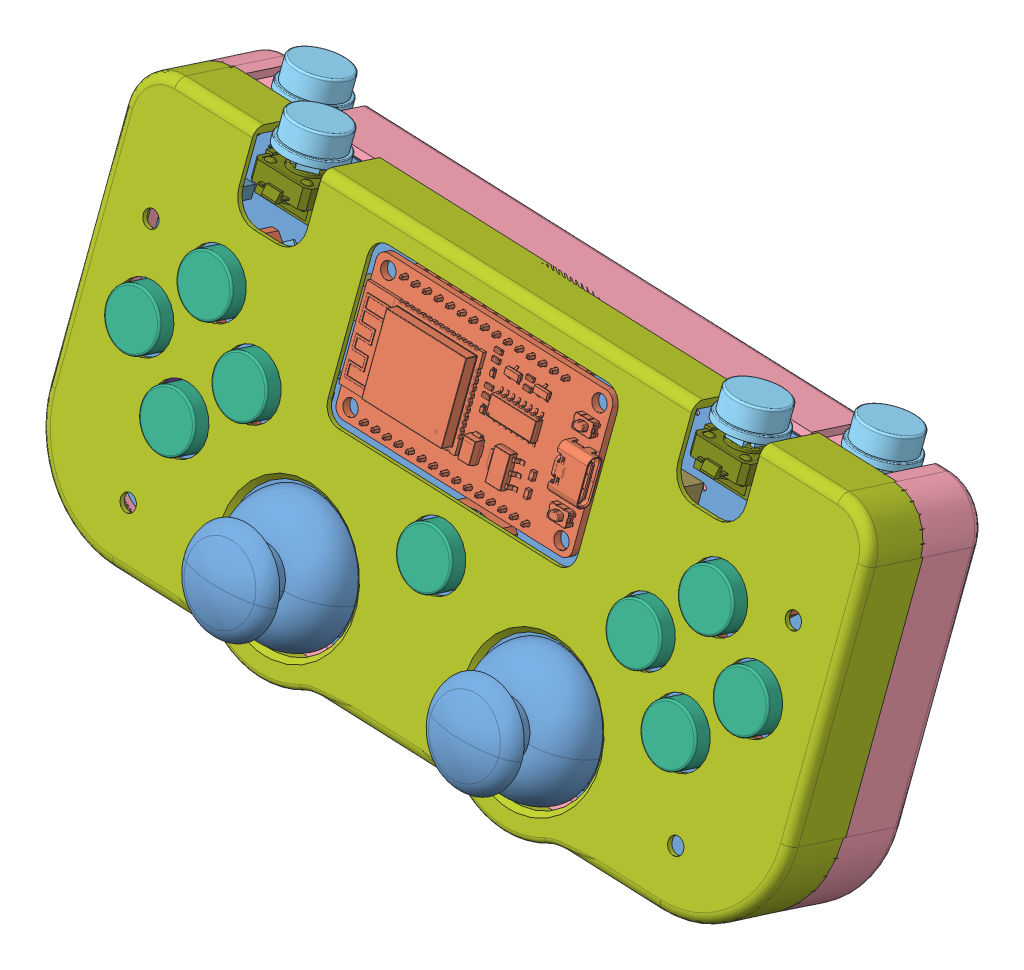
SolidWorks assembly controller, configuration Default. Lengths in mm.
Overall size (166.66 96.06 70.51).
213 component instances, 25 part files, 78 mates.
Components (placement in the parent):
- controller.step-1: controller.step [Default] at (25.4775 3.2443 108.305) x (0.999315 -0.03652 0.006033) z (0.005555 0.30909 0.951017) size (158.62 75.66 29.81)
  - Board.step-1: Board.step [Default] at origin size (158.62 74.17 0.41)
    - Open CASCADE STEP translator 7.5 1.1.1.step-1: Open CASCADE STEP translator 7.5 1.1.1.step [Default] at (0 0 -0.4115) size (158.62 74.17 0.41)
  - SW11.step-1: SW11.step [Default] at origin size (12 13.8 8.01)
    - Switch_Omron_B3F-4000_eec.step-1: Switch_Omron_B3F-4000_eec.step [Default] at (92.7295 35.2468 2.4624) x (0 1 0) z (0 0 1) size (13.8 12 8.01)
      - Omron B3F-4000 1.step-1: Omron B3F-4000 1.step [Default] at (3.1026 -5.4513 -0.4613) size (12 12 5.5)
      - Omron B3F-4000 2.step-1: Omron B3F-4000 2.step [Default] at (3.1026 -5.4513 2.5387) x (-1 0 0) z (0 0 1) size (11 11 0.5)
      - Omron B3F-4000 3.step-1: Omron B3F-4000 3.step [Default] at (3.1026 -5.4513 4.0387) x (1 0 0) z (0 0 -1) size (7.1 7.1 1.5)
      - Omron B3F-4000 4.step-1: Omron B3F-4000 4.step [Default] at (9.5526 -2.4513 -1.9613) x (1 0 0) z (0 -1 0) size (0.9 4 1)
      - Omron B3F-4000 4.step-2: Omron B3F-4000 4.step [Default] at (9.5526 -7.4513 -1.9613) x (1 0 0) z (0 -1 0) size (0.9 4 1)
      - Omron B3F-4000 4_MIR.step-1: Omron B3F-4000 4_MIR.step [Default] at (-3.3474 -2.4513 -1.9613) x (-1 0 0) z (0 1 0) size (0.9 4 1)
      - Omron B3F-4000 4_MIR.step-2: Omron B3F-4000 4_MIR.step [Default] at (-3.3474 -7.4513 -1.9613) x (-1 0 0) z (0 1 0) size (0.9 4 1)
      - Omron B3F-4000 5.step-1: Omron B3F-4000 5.step [Default] at (7.6026 -0.9513 3.0387) size (1.5 1.5 1.2)
      - Omron B3F-4000 5_MIR2.step-1: Omron B3F-4000 5_MIR2.step [Default] at (7.6026 -9.9513 3.0387) x (1 0 0) z (0 0 -1) size (1.5 1.5 1.2)
      - Omron B3F-4000 5_MIR3.step-1: Omron B3F-4000 5_MIR3.step [Default] at (-1.3974 -0.9513 3.0387) x (-1 0 0) z (0 0 -1) size (1.5 1.5 1.2)
      - Omron B3F-4000 5_MIR2_MIR.step-1: Omron B3F-4000 5_MIR2_MIR.step [Default] at (-1.3974 -9.9513 3.0387) x (-1 0 0) z (0 0 1) size (1.5 1.5 1.2)
      - Omron.step-1: Omron.step [Default] at (3.0502 -5.7952 4.0387) size (2.99 0.61 0.02)
  - SW9.step-1: SW9.step [Default] at origin size (6 6 4.5)
    - 7098939168.step-1: 7098939168.step [Default] at (64.389 64.262 0) size (6 6 4.5)
      - Extruded.step-1: Extruded.step [Default] at origin size (6 6 4.5)
  - SW10.step-1: SW10.step [Default] at origin size (6 6 4.5)
    - 7098939168.step-1: 7098939168.step [Default] at (131.953 64.262 0) size (6 6 4.5)
      - Extruded.step-1: Extruded.step [Default] at origin size (6 6 4.5)
  - C5.step-1: C5.step [Default] at origin size (3.81 2.54 11.66)
    - 7094425376.step-1: 7094425376.step [Default] at (34.6711 68.58 -7) size (0.51 0.51 7)
      - Extruded-0.step-1: Extruded-0.step [Default] at origin size (0.51 0.51 7)
    - 7094425376.step-2: 7094425376.step [Default] at (32.1311 68.5801 -7) size (0.51 0.51 7)
      - Extruded-0.step-1: Extruded-0.step [Default] at origin size (0.51 0.51 7)
    - 7098940608.step-1: 7098940608.step [Default] at (33.401 68.58 0) size (3.81 2.54 4.66)
      - Extruded-1.step-1: Extruded-1.step [Default] at origin size (3.81 2.54 4.66)
  - C6.step-1: C6.step [Default] at origin size (3.81 2.54 11.66)
    - 7094425376.step-1: 7094425376.step [Default] at (165.3541 67.31 -7) size (0.51 0.51 7)
      - Extruded-0.step-1: Extruded-0.step [Default] at origin size (0.51 0.51 7)
    - 7094425376.step-2: 7094425376.step [Default] at (162.8141 67.3101 -7) size (0.51 0.51 7)
      - Extruded-0.step-1: Extruded-0.step [Default] at origin size (0.51 0.51 7)
    - 7098940608.step-1: 7098940608.step [Default] at (164.084 67.31 0) size (3.81 2.54 4.66)
      - Extruded-1.step-1: Extruded-1.step [Default] at origin size (3.81 2.54 4.66)
  - S4.step-1: S4.step [Default] at origin size (13.1 13.3 18.3)
    - 6508629744.step-1: 6508629744.step [Default] at (160.742 77.978 -0.4115) x (0 -1 0) z (1 0 0) size (13.3 18.3 13.1)
  - S3.step-1: S3.step [Default] at origin size (13.1 13.3 18.3)
    - 6508631584.step-1: 6508631584.step [Default] at (146.344 77.978 0) x (0 -1 0) z (-1 0 0) size (13.3 18.3 13.1)
  - S2.step-1: S2.step [Default] at origin size (13.1 13.3 18.3)
    - 6508631584.step-1: 6508631584.step [Default] at (49.744 77.978 0) x (0 -1 0) z (-1 0 0) size (13.3 18.3 13.1)
  - S1.step-1: S1.step [Default] at origin size (13.1 13.3 18.3)
    - 6508629744.step-1: 6508629744.step [Default] at (35.346 77.978 -0.4115) x (0 -1 0) z (1 0 0) size (13.3 18.3 13.1)
  - C4.step-1: C4.step [Default] at origin size (4.49 4.49 11.66)
    - 7094425376.step-1: 7094425376.step [Default] at (30.4371 33.138 -7) size (0.51 0.51 7)
      - Extruded-0.step-1: Extruded-0.step [Default] at origin size (0.51 0.51 7)
    - 7094425376.step-2: 7094425376.step [Default] at (28.6411 34.9341 -7) size (0.51 0.51 7)
      - Extruded-0.step-1: Extruded-0.step [Default] at origin size (0.51 0.51 7)
    - 7094424896.step-1: 7094424896.step [Default] at (29.5392 34.036 0) size (4.49 4.49 4.66)
      - Extruded-2.step-1: Extruded-2.step [Default] at origin size (4.49 4.49 4.66)
  - C3.step-1: C3.step [Default] at origin size (4.49 4.49 11.66)
    - 7094425376.step-1: 7094425376.step [Default] at (166.7082 33.9179 -7) size (0.51 0.51 7)
      - Extruded-0.step-1: Extruded-0.step [Default] at origin size (0.51 0.51 7)
    - 7094425376.step-2: 7094425376.step [Default] at (164.9122 32.1219 -7) size (0.51 0.51 7)
      - Extruded-0.step-1: Extruded-0.step [Default] at origin size (0.51 0.51 7)
    - 7098938768.step-1: 7098938768.step [Default] at (165.8102 33.02 0) size (4.49 4.49 4.66)
      - Extruded-3.step-1: Extruded-3.step [Default] at origin size (4.49 4.49 4.66)
  - C2.step-1: C2.step [Default] at origin size (4.49 4.49 11.66)
    - 7094425376.step-1: 7094425376.step [Default] at (55.4293 60.9781 -7) size (0.51 0.51 7)
      - Extruded-0.step-1: Extruded-0.step [Default] at origin size (0.51 0.51 7)
    - 7094425376.step-2: 7094425376.step [Default] at (57.2253 59.182 -7) size (0.51 0.51 7)
      - Extruded-0.step-1: Extruded-0.step [Default] at origin size (0.51 0.51 7)
    - 7094424896.step-1: 7094424896.step [Default] at (56.3272 60.08 0) size (4.49 4.49 4.66)
      - Extruded-2.step-1: Extruded-2.step [Default] at origin size (4.49 4.49 4.66)
  - C1.step-1: C1.step [Default] at origin size (4.49 4.49 11.66)
    - 7094425376.step-1: 7094425376.step [Default] at (139.5122 58.4111 -7) size (0.51 0.51 7)
      - Extruded-0.step-1: Extruded-0.step [Default] at origin size (0.51 0.51 7)
    - 7094425376.step-2: 7094425376.step [Default] at (141.3083 60.2071 -7) size (0.51 0.51 7)
      - Extruded-0.step-1: Extruded-0.step [Default] at origin size (0.51 0.51 7)
    - 7098938768.step-1: 7098938768.step [Default] at (140.4102 59.309 0) size (4.49 4.49 4.66)
      - Extruded-3.step-1: Extruded-3.step [Default] at origin size (4.49 4.49 4.66)
  - SW1.step-1: SW1.step [Default] at origin size (18.24 18.24 8.01)
    - Switch_Omron_B3F-4000_eec.step-1: Switch_Omron_B3F-4000_eec.step [Default] at (48.6404 48.2596 2.4624) x (0.707107 0.707107 0) z (0 0 1) size (13.8 12 8.01)
      - Omron B3F-4000 1.step-1: Omron B3F-4000 1.step [Default] at (3.1026 -5.4513 -0.4613) size (12 12 5.5)
      - Omron B3F-4000 2.step-1: Omron B3F-4000 2.step [Default] at (3.1026 -5.4513 2.5387) x (-1 0 0) z (0 0 1) size (11 11 0.5)
      - Omron B3F-4000 3.step-1: Omron B3F-4000 3.step [Default] at (3.1026 -5.4513 4.0387) x (1 0 0) z (0 0 -1) size (7.1 7.1 1.5)
      - Omron B3F-4000 4.step-1: Omron B3F-4000 4.step [Default] at (9.5526 -2.4513 -1.9613) x (1 0 0) z (0 -1 0) size (0.9 4 1)
      - Omron B3F-4000 4.step-2: Omron B3F-4000 4.step [Default] at (9.5526 -7.4513 -1.9613) x (1 0 0) z (0 -1 0) size (0.9 4 1)
      - Omron B3F-4000 4_MIR.step-1: Omron B3F-4000 4_MIR.step [Default] at (-3.3474 -2.4513 -1.9613) x (-1 0 0) z (0 1 0) size (0.9 4 1)
      - Omron B3F-4000 4_MIR.step-2: Omron B3F-4000 4_MIR.step [Default] at (-3.3474 -7.4513 -1.9613) x (-1 0 0) z (0 1 0) size (0.9 4 1)
      - Omron B3F-4000 5.step-1: Omron B3F-4000 5.step [Default] at (7.6026 -0.9513 3.0387) size (1.5 1.5 1.2)
      - Omron B3F-4000 5_MIR2.step-1: Omron B3F-4000 5_MIR2.step [Default] at (7.6026 -9.9513 3.0387) x (1 0 0) z (0 0 -1) size (1.5 1.5 1.2)
      - Omron B3F-4000 5_MIR3.step-1: Omron B3F-4000 5_MIR3.step [Default] at (-1.3974 -0.9513 3.0387) x (-1 0 0) z (0 0 -1) size (1.5 1.5 1.2)
      - Omron B3F-4000 5_MIR2_MIR.step-1: Omron B3F-4000 5_MIR2_MIR.step [Default] at (-1.3974 -9.9513 3.0387) x (-1 0 0) z (0 0 1) size (1.5 1.5 1.2)
      - Omron.step-1: Omron.step [Default] at (3.0502 -5.7952 4.0387) size (2.99 0.61 0.02)
  - SW2.step-1: SW2.step [Default] at origin size (18.24 18.24 8.01)
    - Switch_Omron_B3F-4000_eec.step-1: Switch_Omron_B3F-4000_eec.step [Default] at (36.8294 60.0706 2.4624) x (0.707107 0.707107 0) z (0 0 1) size (13.8 12 8.01)
      - Omron B3F-4000 1.step-1: Omron B3F-4000 1.step [Default] at (3.1026 -5.4513 -0.4613) size (12 12 5.5)
      - Omron B3F-4000 2.step-1: Omron B3F-4000 2.step [Default] at (3.1026 -5.4513 2.5387) x (-1 0 0) z (0 0 1) size (11 11 0.5)
      - Omron B3F-4000 3.step-1: Omron B3F-4000 3.step [Default] at (3.1026 -5.4513 4.0387) x (1 0 0) z (0 0 -1) size (7.1 7.1 1.5)
      - Omron B3F-4000 4.step-1: Omron B3F-4000 4.step [Default] at (9.5526 -2.4513 -1.9613) x (1 0 0) z (0 -1 0) size (0.9 4 1)
      - Omron B3F-4000 4.step-2: Omron B3F-4000 4.step [Default] at (9.5526 -7.4513 -1.9613) x (1 0 0) z (0 -1 0) size (0.9 4 1)
      - Omron B3F-4000 4_MIR.step-1: Omron B3F-4000 4_MIR.step [Default] at (-3.3474 -2.4513 -1.9613) x (-1 0 0) z (0 1 0) size (0.9 4 1)
      - Omron B3F-4000 4_MIR.step-2: Omron B3F-4000 4_MIR.step [Default] at (-3.3474 -7.4513 -1.9613) x (-1 0 0) z (0 1 0) size (0.9 4 1)
      - Omron B3F-4000 5.step-1: Omron B3F-4000 5.step [Default] at (7.6026 -0.9513 3.0387) size (1.5 1.5 1.2)
      - Omron B3F-4000 5_MIR2.step-1: Omron B3F-4000 5_MIR2.step [Default] at (7.6026 -9.9513 3.0387) x (1 0 0) z (0 0 -1) size (1.5 1.5 1.2)
      - Omron B3F-4000 5_MIR3.step-1: Omron B3F-4000 5_MIR3.step [Default] at (-1.3974 -0.9513 3.0387) x (-1 0 0) z (0 0 -1) size (1.5 1.5 1.2)
      - Omron B3F-4000 5_MIR2_MIR.step-1: Omron B3F-4000 5_MIR2_MIR.step [Default] at (-1.3974 -9.9513 3.0387) x (-1 0 0) z (0 0 1) size (1.5 1.5 1.2)
      - Omron.step-1: Omron.step [Default] at (3.0502 -5.7952 4.0387) size (2.99 0.61 0.02)
  - SW3.step-1: SW3.step [Default] at origin size (18.24 18.24 8.01)
    - Switch_Omron_B3F-4000_eec.step-1: Switch_Omron_B3F-4000_eec.step [Default] at (25.0184 48.2596 2.4624) x (0.707107 0.707107 0) z (0 0 1) size (13.8 12 8.01)
      - Omron B3F-4000 1.step-1: Omron B3F-4000 1.step [Default] at (3.1026 -5.4513 -0.4613) size (12 12 5.5)
      - Omron B3F-4000 2.step-1: Omron B3F-4000 2.step [Default] at (3.1026 -5.4513 2.5387) x (-1 0 0) z (0 0 1) size (11 11 0.5)
      - Omron B3F-4000 3.step-1: Omron B3F-4000 3.step [Default] at (3.1026 -5.4513 4.0387) x (1 0 0) z (0 0 -1) size (7.1 7.1 1.5)
      - Omron B3F-4000 4.step-1: Omron B3F-4000 4.step [Default] at (9.5526 -2.4513 -1.9613) x (1 0 0) z (0 -1 0) size (0.9 4 1)
      - Omron B3F-4000 4.step-2: Omron B3F-4000 4.step [Default] at (9.5526 -7.4513 -1.9613) x (1 0 0) z (0 -1 0) size (0.9 4 1)
      - Omron B3F-4000 4_MIR.step-1: Omron B3F-4000 4_MIR.step [Default] at (-3.3474 -2.4513 -1.9613) x (-1 0 0) z (0 1 0) size (0.9 4 1)
      - Omron B3F-4000 4_MIR.step-2: Omron B3F-4000 4_MIR.step [Default] at (-3.3474 -7.4513 -1.9613) x (-1 0 0) z (0 1 0) size (0.9 4 1)
      - Omron B3F-4000 5.step-1: Omron B3F-4000 5.step [Default] at (7.6026 -0.9513 3.0387) size (1.5 1.5 1.2)
      - Omron B3F-4000 5_MIR2.step-1: Omron B3F-4000 5_MIR2.step [Default] at (7.6026 -9.9513 3.0387) x (1 0 0) z (0 0 -1) size (1.5 1.5 1.2)
      - Omron B3F-4000 5_MIR3.step-1: Omron B3F-4000 5_MIR3.step [Default] at (-1.3974 -0.9513 3.0387) x (-1 0 0) z (0 0 -1) size (1.5 1.5 1.2)
      - Omron B3F-4000 5_MIR2_MIR.step-1: Omron B3F-4000 5_MIR2_MIR.step [Default] at (-1.3974 -9.9513 3.0387) x (-1 0 0) z (0 0 1) size (1.5 1.5 1.2)
      - Omron.step-1: Omron.step [Default] at (3.0502 -5.7952 4.0387) size (2.99 0.61 0.02)
  - SW4.step-1: SW4.step [Default] at origin size (18.24 18.24 8.01)
    - Switch_Omron_B3F-4000_eec.step-1: Switch_Omron_B3F-4000_eec.step [Default] at (36.8294 36.4486 2.4624) x (0.707107 0.707107 0) z (0 0 1) size (13.8 12 8.01)
      - Omron B3F-4000 1.step-1: Omron B3F-4000 1.step [Default] at (3.1026 -5.4513 -0.4613) size (12 12 5.5)
      - Omron B3F-4000 2.step-1: Omron B3F-4000 2.step [Default] at (3.1026 -5.4513 2.5387) x (-1 0 0) z (0 0 1) size (11 11 0.5)
      - Omron B3F-4000 3.step-1: Omron B3F-4000 3.step [Default] at (3.1026 -5.4513 4.0387) x (1 0 0) z (0 0 -1) size (7.1 7.1 1.5)
      - Omron B3F-4000 4.step-1: Omron B3F-4000 4.step [Default] at (9.5526 -2.4513 -1.9613) x (1 0 0) z (0 -1 0) size (0.9 4 1)
      - Omron B3F-4000 4.step-2: Omron B3F-4000 4.step [Default] at (9.5526 -7.4513 -1.9613) x (1 0 0) z (0 -1 0) size (0.9 4 1)
      - Omron B3F-4000 4_MIR.step-1: Omron B3F-4000 4_MIR.step [Default] at (-3.3474 -2.4513 -1.9613) x (-1 0 0) z (0 1 0) size (0.9 4 1)
      - Omron B3F-4000 4_MIR.step-2: Omron B3F-4000 4_MIR.step [Default] at (-3.3474 -7.4513 -1.9613) x (-1 0 0) z (0 1 0) size (0.9 4 1)
      - Omron B3F-4000 5.step-1: Omron B3F-4000 5.step [Default] at (7.6026 -0.9513 3.0387) size (1.5 1.5 1.2)
      - Omron B3F-4000 5_MIR2.step-1: Omron B3F-4000 5_MIR2.step [Default] at (7.6026 -9.9513 3.0387) x (1 0 0) z (0 0 -1) size (1.5 1.5 1.2)
      - Omron B3F-4000 5_MIR3.step-1: Omron B3F-4000 5_MIR3.step [Default] at (-1.3974 -0.9513 3.0387) x (-1 0 0) z (0 0 -1) size (1.5 1.5 1.2)
      - Omron B3F-4000 5_MIR2_MIR.step-1: Omron B3F-4000 5_MIR2_MIR.step [Default] at (-1.3974 -9.9513 3.0387) x (-1 0 0) z (0 0 1) size (1.5 1.5 1.2)
      - Omron.step-1: Omron.step [Default] at (3.0502 -5.7952 4.0387) size (2.99 0.61 0.02)
  - SW8.step-1: SW8.step [Default] at origin size (18.24 18.24 8.01)
    - Switch_Omron_B3F-4000_eec.step-1: Switch_Omron_B3F-4000_eec.step [Default] at (147.1924 36.4486 2.4624) x (0.707107 0.707107 0) z (0 0 1) size (13.8 12 8.01)
      - Omron B3F-4000 1.step-1: Omron B3F-4000 1.step [Default] at (3.1026 -5.4513 -0.4613) size (12 12 5.5)
      - Omron B3F-4000 2.step-1: Omron B3F-4000 2.step [Default] at (3.1026 -5.4513 2.5387) x (-1 0 0) z (0 0 1) size (11 11 0.5)
      - Omron B3F-4000 3.step-1: Omron B3F-4000 3.step [Default] at (3.1026 -5.4513 4.0387) x (1 0 0) z (0 0 -1) size (7.1 7.1 1.5)
      - Omron B3F-4000 4.step-1: Omron B3F-4000 4.step [Default] at (9.5526 -2.4513 -1.9613) x (1 0 0) z (0 -1 0) size (0.9 4 1)
      - Omron B3F-4000 4.step-2: Omron B3F-4000 4.step [Default] at (9.5526 -7.4513 -1.9613) x (1 0 0) z (0 -1 0) size (0.9 4 1)
      - Omron B3F-4000 4_MIR.step-1: Omron B3F-4000 4_MIR.step [Default] at (-3.3474 -2.4513 -1.9613) x (-1 0 0) z (0 1 0) size (0.9 4 1)
      - Omron B3F-4000 4_MIR.step-2: Omron B3F-4000 4_MIR.step [Default] at (-3.3474 -7.4513 -1.9613) x (-1 0 0) z (0 1 0) size (0.9 4 1)
      - Omron B3F-4000 5.step-1: Omron B3F-4000 5.step [Default] at (7.6026 -0.9513 3.0387) size (1.5 1.5 1.2)
      - Omron B3F-4000 5_MIR2.step-1: Omron B3F-4000 5_MIR2.step [Default] at (7.6026 -9.9513 3.0387) x (1 0 0) z (0 0 -1) size (1.5 1.5 1.2)
      - Omron B3F-4000 5_MIR3.step-1: Omron B3F-4000 5_MIR3.step [Default] at (-1.3974 -0.9513 3.0387) x (-1 0 0) z (0 0 -1) size (1.5 1.5 1.2)
      - Omron B3F-4000 5_MIR2_MIR.step-1: Omron B3F-4000 5_MIR2_MIR.step [Default] at (-1.3974 -9.9513 3.0387) x (-1 0 0) z (0 0 1) size (1.5 1.5 1.2)
      - Omron.step-1: Omron.step [Default] at (3.0502 -5.7952 4.0387) size (2.99 0.61 0.02)
  - SW7.step-1: SW7.step [Default] at origin size (18.24 18.24 8.01)
    - Switch_Omron_B3F-4000_eec.step-1: Switch_Omron_B3F-4000_eec.step [Default] at (135.3813 48.2596 2.4624) x (0.707107 0.707107 0) z (0 0 1) size (13.8 12 8.01)
      - Omron B3F-4000 1.step-1: Omron B3F-4000 1.step [Default] at (3.1026 -5.4513 -0.4613) size (12 12 5.5)
      - Omron B3F-4000 2.step-1: Omron B3F-4000 2.step [Default] at (3.1026 -5.4513 2.5387) x (-1 0 0) z (0 0 1) size (11 11 0.5)
      - Omron B3F-4000 3.step-1: Omron B3F-4000 3.step [Default] at (3.1026 -5.4513 4.0387) x (1 0 0) z (0 0 -1) size (7.1 7.1 1.5)
      - Omron B3F-4000 4.step-1: Omron B3F-4000 4.step [Default] at (9.5526 -2.4513 -1.9613) x (1 0 0) z (0 -1 0) size (0.9 4 1)
      - Omron B3F-4000 4.step-2: Omron B3F-4000 4.step [Default] at (9.5526 -7.4513 -1.9613) x (1 0 0) z (0 -1 0) size (0.9 4 1)
      - Omron B3F-4000 4_MIR.step-1: Omron B3F-4000 4_MIR.step [Default] at (-3.3474 -2.4513 -1.9613) x (-1 0 0) z (0 1 0) size (0.9 4 1)
      - Omron B3F-4000 4_MIR.step-2: Omron B3F-4000 4_MIR.step [Default] at (-3.3474 -7.4513 -1.9613) x (-1 0 0) z (0 1 0) size (0.9 4 1)
      - Omron B3F-4000 5.step-1: Omron B3F-4000 5.step [Default] at (7.6026 -0.9513 3.0387) size (1.5 1.5 1.2)
      - Omron B3F-4000 5_MIR2.step-1: Omron B3F-4000 5_MIR2.step [Default] at (7.6026 -9.9513 3.0387) x (1 0 0) z (0 0 -1) size (1.5 1.5 1.2)
      - Omron B3F-4000 5_MIR3.step-1: Omron B3F-4000 5_MIR3.step [Default] at (-1.3974 -0.9513 3.0387) x (-1 0 0) z (0 0 -1) size (1.5 1.5 1.2)
      - Omron B3F-4000 5_MIR2_MIR.step-1: Omron B3F-4000 5_MIR2_MIR.step [Default] at (-1.3974 -9.9513 3.0387) x (-1 0 0) z (0 0 1) size (1.5 1.5 1.2)
      - Omron.step-1: Omron.step [Default] at (3.0502 -5.7952 4.0387) size (2.99 0.61 0.02)
  - SW6.step-1: SW6.step [Default] at origin size (18.24 18.24 8.01)
    - Switch_Omron_B3F-4000_eec.step-1: Switch_Omron_B3F-4000_eec.step [Default] at (147.1924 60.0706 2.4624) x (0.707107 0.707107 0) z (0 0 1) size (13.8 12 8.01)
      - Omron B3F-4000 1.step-1: Omron B3F-4000 1.step [Default] at (3.1026 -5.4513 -0.4613) size (12 12 5.5)
      - Omron B3F-4000 2.step-1: Omron B3F-4000 2.step [Default] at (3.1026 -5.4513 2.5387) x (-1 0 0) z (0 0 1) size (11 11 0.5)
      - Omron B3F-4000 3.step-1: Omron B3F-4000 3.step [Default] at (3.1026 -5.4513 4.0387) x (1 0 0) z (0 0 -1) size (7.1 7.1 1.5)
      - Omron B3F-4000 4.step-1: Omron B3F-4000 4.step [Default] at (9.5526 -2.4513 -1.9613) x (1 0 0) z (0 -1 0) size (0.9 4 1)
      - Omron B3F-4000 4.step-2: Omron B3F-4000 4.step [Default] at (9.5526 -7.4513 -1.9613) x (1 0 0) z (0 -1 0) size (0.9 4 1)
      - Omron B3F-4000 4_MIR.step-1: Omron B3F-4000 4_MIR.step [Default] at (-3.3474 -2.4513 -1.9613) x (-1 0 0) z (0 1 0) size (0.9 4 1)
      - Omron B3F-4000 4_MIR.step-2: Omron B3F-4000 4_MIR.step [Default] at (-3.3474 -7.4513 -1.9613) x (-1 0 0) z (0 1 0) size (0.9 4 1)
      - Omron B3F-4000 5.step-1: Omron B3F-4000 5.step [Default] at (7.6026 -0.9513 3.0387) size (1.5 1.5 1.2)
      - Omron B3F-4000 5_MIR2.step-1: Omron B3F-4000 5_MIR2.step [Default] at (7.6026 -9.9513 3.0387) x (1 0 0) z (0 0 -1) size (1.5 1.5 1.2)
      - Omron B3F-4000 5_MIR3.step-1: Omron B3F-4000 5_MIR3.step [Default] at (-1.3974 -0.9513 3.0387) x (-1 0 0) z (0 0 -1) size (1.5 1.5 1.2)
      - Omron B3F-4000 5_MIR2_MIR.step-1: Omron B3F-4000 5_MIR2_MIR.step [Default] at (-1.3974 -9.9513 3.0387) x (-1 0 0) z (0 0 1) size (1.5 1.5 1.2)
      - Omron.step-1: Omron.step [Default] at (3.0502 -5.7952 4.0387) size (2.99 0.61 0.02)
  - SW5.step-1: SW5.step [Default] at origin size (18.24 18.24 8.01)
    - Switch_Omron_B3F-4000_eec.step-1: Switch_Omron_B3F-4000_eec.step [Default] at (159.0034 48.2596 2.4624) x (0.707107 0.707107 0) z (0 0 1) size (13.8 12 8.01)
      - Omron B3F-4000 1.step-1: Omron B3F-4000 1.step [Default] at (3.1026 -5.4513 -0.4613) size (12 12 5.5)
      - Omron B3F-4000 2.step-1: Omron B3F-4000 2.step [Default] at (3.1026 -5.4513 2.5387) x (-1 0 0) z (0 0 1) size (11 11 0.5)
      - Omron B3F-4000 3.step-1: Omron B3F-4000 3.step [Default] at (3.1026 -5.4513 4.0387) x (1 0 0) z (0 0 -1) size (7.1 7.1 1.5)
      - Omron B3F-4000 4.step-1: Omron B3F-4000 4.step [Default] at (9.5526 -2.4513 -1.9613) x (1 0 0) z (0 -1 0) size (0.9 4 1)
      - Omron B3F-4000 4.step-2: Omron B3F-4000 4.step [Default] at (9.5526 -7.4513 -1.9613) x (1 0 0) z (0 -1 0) size (0.9 4 1)
      - Omron B3F-4000 4_MIR.step-1: Omron B3F-4000 4_MIR.step [Default] at (-3.3474 -2.4513 -1.9613) x (-1 0 0) z (0 1 0) size (0.9 4 1)
      - Omron B3F-4000 4_MIR.step-2: Omron B3F-4000 4_MIR.step [Default] at (-3.3474 -7.4513 -1.9613) x (-1 0 0) z (0 1 0) size (0.9 4 1)
      - Omron B3F-4000 5.step-1: Omron B3F-4000 5.step [Default] at (7.6026 -0.9513 3.0387) size (1.5 1.5 1.2)
      - Omron B3F-4000 5_MIR2.step-1: Omron B3F-4000 5_MIR2.step [Default] at (7.6026 -9.9513 3.0387) x (1 0 0) z (0 0 -1) size (1.5 1.5 1.2)
      - Omron B3F-4000 5_MIR3.step-1: Omron B3F-4000 5_MIR3.step [Default] at (-1.3974 -0.9513 3.0387) x (-1 0 0) z (0 0 -1) size (1.5 1.5 1.2)
      - Omron B3F-4000 5_MIR2_MIR.step-1: Omron B3F-4000 5_MIR2_MIR.step [Default] at (-1.3974 -9.9513 3.0387) x (-1 0 0) z (0 0 1) size (1.5 1.5 1.2)
      - Omron.step-1: Omron.step [Default] at (3.0502 -5.7952 4.0387) size (2.99 0.61 0.02)
- COM-09032-1: COM-09032 [Default] at (97.4277 22.5889 101.5976) x (0.999315 -0.03652 0.006033) z (-0.036596 -0.950331 0.309081) size (26.67 34.67 27.62)
- COM-09032-2: COM-09032 [Default] at (151.2136 20.6099 101.9266) x (0.999315 -0.03652 0.006033) z (-0.036596 -0.950331 0.309081) size (26.67 34.67 27.62)
- esp32_30pin-1: esp32_30pin [По умолчанию] at (148.2005 52.2986 104.8892) x (0.036596 0.950331 -0.309081) z (0.005555 0.30909 0.951017) size (29 52.96 13.53)
- powerboost 1000c.f3d v3-1: powerboost 1000c.f3d v3 [Default] at (151.8493 9.8112 109.6265) x (0.036596 0.950331 -0.309081) z (-0.005555 -0.30909 -0.951017) size (36.64 22.86 4.38)
- Part1-1: Part1 [Default] at (45.204 24.8437 87.0675) x (0.999315 -0.03652 0.006033) z (-0.036596 -0.950331 0.309081) size (163.63 14.65 81.83)
- 12mm Push Button Cap-1: 12mm Push Button Cap [Default] at (179.9154 32.315 103.4225) x (0.640311 -0.731594 0.234035) z (-0.768096 -0.607647 0.201977) size (13 8.2 13)
- 12mm Push Button Cap-2: 12mm Push Button Cap [Default] at (180.7799 54.7638 96.1214) x (0.640311 -0.731594 0.234035) z (-0.768096 -0.607647 0.201977) size (13 8.2 13)
- 12mm Push Button Cap-3: 12mm Push Button Cap [Default] at (168.5447 43.9708 99.7007) x (0.640311 -0.731594 0.234035) z (-0.768096 -0.607647 0.201977) size (13 8.2 13)
- 12mm Push Button Cap-4: 12mm Push Button Cap [Default] at (192.1505 43.1081 99.8432) x (0.191146 0.933167 -0.304405) z (0.981546 -0.183474 0.053898) size (13 8.2 13)
- 12mm Push Button Cap-5: 12mm Push Button Cap [Default] at (125.0234 37.7106 101.9895) x (0.640311 -0.731594 0.234035) z (-0.768096 -0.607647 0.201977) size (13 8.2 13)
- 12mm Push Button Cap TALL-1: 12mm Push Button Cap TALL [Default] at (192.1505 43.1081 99.8432) x (-0.613772 -0.749763 0.247265) z (-0.789464 0.585081 -0.185546) size (13 12.9 13)
- top_plate-1: top_plate [Default] at (203.8676 27.2141 113.1422) x (-0.999315 0.03652 -0.006033) z (-0.036596 -0.950331 0.309081) size (163.63 13.51 81.83)
- 12mm Push Button Cap-6: 12mm Push Button Cap [Default] at (58.2574 48.0013 99.0349) x (0.7195 -0.661708 0.210859) z (-0.69447 -0.683086 0.226066) size (13 8.2 13)
- 12mm Push Button Cap-7: 12mm Push Button Cap [Default] at (70.4925 58.7943 95.4556) x (0.640311 -0.731594 0.234035) z (-0.768096 -0.607647 0.201977) size (13 8.2 13)
- 12mm Push Button Cap-8: 12mm Push Button Cap [Default] at (69.628 36.3456 102.7567) x (0.640311 -0.731594 0.234035) z (-0.768096 -0.607647 0.201977) size (13 8.2 13)
- 12mm Push Button Cap-9: 12mm Push Button Cap [Default] at (81.8632 47.1386 99.1774) x (0.640311 -0.731594 0.234035) z (-0.768096 -0.607647 0.201977) size (13 8.2 13)
- 12mm Push Button Cap TALL-6: 12mm Push Button Cap TALL [Default] at (180.7799 54.7638 96.1214) x (-0.999145 0.040688 -0.007388) z (0.040979 0.950162 -0.309051) size (13 12.9 13)
- 12mm Push Button Cap TALL-7: 12mm Push Button Cap TALL [Default] at (125.0234 37.7106 101.9895) x (-0.613772 -0.749763 0.247265) z (-0.789464 0.585081 -0.185546) size (13 12.9 13)
- 12mm Push Button Cap TALL-8: 12mm Push Button Cap TALL [Default] at (58.2574 48.0013 99.0349) x (-0.502403 -0.821427 0.269906) z (-0.864616 0.479293 -0.150725) size (13 12.9 13)
- 12mm Push Button Cap TALL-9: 12mm Push Button Cap TALL [Default] at (69.628 36.3456 102.7567) x (-0.776873 -0.597476 0.198723) z (-0.629633 0.739923 -0.236805) size (13 12.9 13)
- 12mm Push Button Cap TALL-10: 12mm Push Button Cap TALL [Default] at (168.5447 43.9708 99.7007) x (-0.613772 -0.749763 0.247265) z (-0.789464 0.585081 -0.185546) size (13 12.9 13)
- 12mm Push Button Cap TALL-11: 12mm Push Button Cap TALL [Default] at (179.9154 32.315 103.4225) x (-0.613772 -0.749763 0.247265) z (-0.789464 0.585081 -0.185546) size (13 12.9 13)
- 12mm Push Button Cap TALL-12: 12mm Push Button Cap TALL [Default] at (70.4925 58.7943 95.4556) x (-0.78112 -0.592451 0.197115) z (-0.624357 0.743953 -0.238145) size (13 12.9 13)
- 12mm Push Button Cap TALL-13: 12mm Push Button Cap TALL [Default] at (81.8632 47.1386 99.1774) x (-0.613772 -0.749763 0.247265) z (-0.789464 0.585081 -0.185546) size (13 12.9 13)
- 12mm Push Button Cap-10: 12mm Push Button Cap [Default] at (174.8391 80.1008 90.3398) x (0.005555 0.30909 0.951017) z (-0.999315 0.03652 -0.006033) size (13 8.2 13)
- 12mm Push Button Cap-11: 12mm Push Button Cap [Default] at (189.1416 74.8115 75.7701) x (0.285665 -0.30633 -0.908051) z (0.95763 0.055062 0.282687) size (13 8.2 13)
- 12mm Push Button Cap-12: 12mm Push Button Cap [Default] at (63.8315 79.391 75.0136) x (0.654 0.211082 0.72645) z (-0.755609 0.228724 0.613792) size (13 8.2 13)
- 12mm Push Button Cap-13: 12mm Push Button Cap [Default] at (78.3053 83.6287 89.757) x (0.680165 0.202908 0.704417) z (-0.732145 0.236005 0.638957) size (13 8.2 13)
Mates (geometry in assembly coordinates):
- Coincident2: coincident anti-aligned: plane of controller.step-1/Board.step-1/Open CASCADE STEP translator 7.5 1.1.1.step-1 through (125.235 44.2553 94.3933) normal (0.005555 0.30909 0.951017); plane of COM-09032-1 through (97.4277 22.5889 101.5976) normal (-0.005555 -0.30909 -0.951017)
- Parallel6: parallel aligned: plane of controller.step-1/Board.step-1/Open CASCADE STEP translator 7.5 1.1.1.step-1 through (184.0564 5.6611 106.1606) normal (-0.036596 -0.950331 0.309081); plane of COM-09032-1 through (96.5277 11.5931 105.1766) normal (-0.036596 -0.950331 0.309081)
- Distance1: distance = 2.7383 mm aligned: plane of COM-09032-1 through (96.5277 11.5931 105.1766) normal (-0.036596 -0.950331 0.309081); plane of controller.step-1/Board.step-1/Open CASCADE STEP translator 7.5 1.1.1.step-1 through (184.0564 5.6611 106.1606) normal (-0.036596 -0.950331 0.309081)
- Distance3: distance = 44.4205 mm aligned: plane of COM-09032-1 through (89.0631 7.9437 82.7993) normal (-0.999315 0.03652 -0.006033); plane of controller.step-1/Board.step-1/Open CASCADE STEP translator 7.5 1.1.1.step-1 through (45.2762 28.8622 99.4306) normal (-0.999315 0.03652 -0.006033)
- Coincident17: coincident anti-aligned: plane of controller.step-1/Board.step-1/Open CASCADE STEP translator 7.5 1.1.1.step-1 through (125.235 44.2553 94.3933) normal (0.005555 0.30909 0.951017); plane of COM-09032-2 through (151.2136 20.6099 101.9266) normal (-0.005555 -0.30909 -0.951017)
- Parallel8: parallel: line of controller.step-1/Board.step-1/Open CASCADE STEP translator 7.5 1.1.1.step-1 through (184.0564 5.6611 106.1606) axis (-0.999315 0.03652 -0.006033); plane of COM-09032-2 through (150.3136 9.6141 105.5056) normal (-0.036596 -0.950331 0.309081)
- Distance4: distance = 44.5042 mm aligned: plane of COM-09032-2 through (158.7131 5.3849 83.2241) normal (0.999315 -0.03652 0.006033); plane of controller.step-1/Board.step-1/Open CASCADE STEP translator 7.5 1.1.1.step-1 through (205.5752 69.415 85.3143) normal (0.999315 -0.03652 0.006033)
- Distance5: distance = 2.7243 mm aligned: plane of COM-09032-2 through (150.3136 9.6141 105.5056) normal (-0.036596 -0.950331 0.309081); plane of controller.step-1/Board.step-1/Open CASCADE STEP translator 7.5 1.1.1.step-1 through (184.0564 5.6611 106.1606) normal (-0.036596 -0.950331 0.309081)
- Parallel9: parallel anti-aligned: plane of controller.step-1/Board.step-1/Open CASCADE STEP translator 7.5 1.1.1.step-1 through (125.235 44.2553 94.3933) normal (0.005555 0.30909 0.951017); plane of esp32_30pin-1 through (125.2811 64.1247 99.5019) normal (-0.005555 -0.30909 -0.951017)
- Parallel10: parallel aligned: plane of controller.step-1/Board.step-1/Open CASCADE STEP translator 7.5 1.1.1.step-1 through (53.639 81.0107 82.433) normal (0.036596 0.950331 -0.309081); plane of esp32_30pin-1 through (149.7954 77.028 95.165) normal (0.036596 0.950331 -0.309081)
- Parallel11: parallel aligned: plane of controller.step-1/Board.step-1/Open CASCADE STEP translator 7.5 1.1.1.step-1 through (45.2762 28.8622 99.4306) normal (-0.999315 0.03652 -0.006033); plane of esp32_30pin-1 through (99.7565 76.9533 95.4816) normal (-0.999315 0.03652 -0.006033)
- Distance10: distance = 53.9602 mm aligned: plane of esp32_30pin-1 through (150.8059 51.296 103.5223) normal (0.999315 -0.03652 0.006033); plane of controller.step-1/Board.step-1/Open CASCADE STEP translator 7.5 1.1.1.step-1 through (205.5752 69.415 85.3143) normal (0.999315 -0.03652 0.006033)
- Distance11: distance = 4.2011 mm aligned: plane of esp32_30pin-1 through (149.7954 77.028 95.165) normal (0.036596 0.950331 -0.309081); plane of controller.step-1/Board.step-1/Open CASCADE STEP translator 7.5 1.1.1.step-1 through (53.639 81.0107 82.433) normal (0.036596 0.950331 -0.309081)
- Parallel15: parallel aligned: plane of controller.step-1/Board.step-1/Open CASCADE STEP translator 7.5 1.1.1.step-1 through (125.2328 44.1282 94.002) normal (-0.005555 -0.30909 -0.951017); plane of powerboost 1000c.f3d v3-1 through (124.3289 22.2845 91.0122) normal (-0.005555 -0.30909 -0.951017)
- Parallel18: parallel aligned: plane of controller.step-1/Board.step-1/Open CASCADE STEP translator 7.5 1.1.1.step-1 through (184.0564 5.6611 106.1606) normal (-0.036596 -0.950331 0.309081); plane of powerboost 1000c.f3d v3-1 through (135.0976 5.1606 98.1972) normal (-0.036596 -0.950331 0.309081)
- Distance13: distance = 11 mm anti-aligned: plane of esp32_30pin-1 through (125.2811 64.1247 99.5019) normal (-0.005555 -0.30909 -0.951017); plane of controller.step-1/Board.step-1/Open CASCADE STEP translator 7.5 1.1.1.step-1 through (125.235 44.2553 94.3933) normal (0.005555 0.30909 0.951017)
- Parallel19: parallel anti-aligned: plane of controller.step-1/Board.step-1/Open CASCADE STEP translator 7.5 1.1.1.step-1 through (125.2328 44.1282 94.002) normal (-0.005555 -0.30909 -0.951017); plane of Part1-1 through (64.2478 24.457 88.1335) normal (0.005555 0.30909 0.951017)
- Parallel20: parallel anti-aligned: plane of controller.step-1/Board.step-1/Open CASCADE STEP translator 7.5 1.1.1.step-1 through (53.639 81.0107 82.433) normal (0.036596 0.950331 -0.309081); plane of Part1-1 through (199.4285 72.6136 70.641) normal (-0.036596 -0.950331 0.309081)
- Parallel21: parallel aligned: plane of controller.step-1/Board.step-1/Open CASCADE STEP translator 7.5 1.1.1.step-1 through (205.5752 69.415 85.3143) normal (0.999315 -0.03652 0.006033); plane of Part1-1 through (206.2192 18.9593 88.0395) normal (0.999315 -0.03652 0.006033)
- Distance14: distance = 1 mm anti-aligned: plane of controller.step-1/Board.step-1/Open CASCADE STEP translator 7.5 1.1.1.step-1 through (53.639 81.0107 82.433) normal (0.036596 0.950331 -0.309081); plane of Part1-1 through (199.4285 72.6136 70.641) normal (-0.036596 -0.950331 0.309081)
- Distance15: distance = 12 mm anti-aligned: plane of Part1-1 through (64.2478 24.457 88.1335) normal (0.005555 0.30909 0.951017); plane of controller.step-1/Board.step-1/Open CASCADE STEP translator 7.5 1.1.1.step-1 through (125.2328 44.1282 94.002) normal (-0.005555 -0.30909 -0.951017)
- Distance16: distance = 1 mm anti-aligned: plane of Part1-1 through (45.9894 71.2259 71.9882) normal (0.999315 -0.03652 0.006033); plane of controller.step-1/Board.step-1/Open CASCADE STEP translator 7.5 1.1.1.step-1 through (45.2762 28.8622 99.4306) normal (-0.999315 0.03652 -0.006033)
- Parallel22: parallel aligned: plane of Part1-1 through (199.4834 74.0391 70.1774) normal (0.036596 0.950331 -0.309081); plane of Part1-2 through (56.1405 217.4734 494.2233) normal (0.036596 0.950331 -0.309081)
- Coincident19: coincident aligned: plane of Part1-1 through (63.4535 3.667 93.8435) normal (-0.036596 -0.950331 0.309081); plane of Part1-2 through (186.3758 137.3705 519.4968) normal (-0.036596 -0.950331 0.309081)
- Coincident20: coincident aligned: plane of Part1-1 through (63.4535 3.667 93.8435) normal (-0.036596 -0.950331 0.309081); plane of Part1-2 through (186.3758 137.3705 519.4968) normal (-0.036596 -0.950331 0.309081)
- Coincident21: coincident aligned: plane of Part1-1 through (44.4904 71.2807 71.9792) normal (-0.999315 0.03652 -0.006033); plane of Part1-2 through (45.1876 163.04 511.9786) normal (-0.999315 0.03652 -0.006033)
- Concentric11: concentric aligned: circle of controller.step-1/SW8.step-1/Switch_Omron_B3F-4000_eec.step-1/Omron B3F-4000 3.step-1; cylinder of 12mm Push Button Cap-1 through (179.9476 34.1078 108.9384) axis (-0.005555 -0.30909 -0.951017) radius 5.8
- Distance17: distance = 11 mm aligned: plane of 12mm Push Button Cap-1 through (179.9476 34.1078 108.9384) normal (0.005555 0.30909 0.951017); plane of controller.step-1/Board.step-1/Open CASCADE STEP translator 7.5 1.1.1.step-1 through (125.235 44.2553 94.3933) normal (0.005555 0.30909 0.951017)
- Distance18: distance = 11 mm aligned: plane of 12mm Push Button Cap-4 through (192.1828 44.9008 105.3591) normal (0.005555 0.30909 0.951017); plane of controller.step-1/Board.step-1/Open CASCADE STEP translator 7.5 1.1.1.step-1 through (125.235 44.2553 94.3933) normal (0.005555 0.30909 0.951017)
- Distance19: distance = 11 mm aligned: plane of 12mm Push Button Cap-2 through (180.8121 56.5565 101.6373) normal (0.005555 0.30909 0.951017); plane of controller.step-1/Board.step-1/Open CASCADE STEP translator 7.5 1.1.1.step-1 through (125.235 44.2553 94.3933) normal (0.005555 0.30909 0.951017)
- Distance20: distance = 11 mm aligned: plane of 12mm Push Button Cap-3 through (168.5769 45.7635 105.2166) normal (0.005555 0.30909 0.951017); plane of controller.step-1/Board.step-1/Open CASCADE STEP translator 7.5 1.1.1.step-1 through (125.235 44.2553 94.3933) normal (0.005555 0.30909 0.951017)
- Concentric12: concentric anti-aligned: circle of controller.step-1/SW5.step-1/Switch_Omron_B3F-4000_eec.step-1/Omron B3F-4000 3.step-1; circle of 12mm Push Button Cap-4
- Concentric13: concentric anti-aligned: circle of controller.step-1/SW7.step-1/Switch_Omron_B3F-4000_eec.step-1/Omron B3F-4000 3.step-1; circle of 12mm Push Button Cap-3
- Concentric14: concentric aligned: circle of controller.step-1/SW6.step-1/Switch_Omron_B3F-4000_eec.step-1/Omron B3F-4000 3.step-1; circle of 12mm Push Button Cap-2
- Distance21: distance = 11 mm aligned: plane of 12mm Push Button Cap-5 through (125.0556 39.5033 107.5054) normal (0.005555 0.30909 0.951017); plane of controller.step-1/Board.step-1/Open CASCADE STEP translator 7.5 1.1.1.step-1 through (125.235 44.2553 94.3933) normal (0.005555 0.30909 0.951017)
- Concentric15: concentric anti-aligned: circle of controller.step-1/SW11.step-1/Switch_Omron_B3F-4000_eec.step-1/Omron B3F-4000 3.step-1; circle of 12mm Push Button Cap-5
- Concentric16: concentric anti-aligned: circle of 12mm Push Button Cap-4; circle of 12mm Push Button Cap TALL-1
- Coincident33: coincident aligned: plane of 12mm Push Button Cap-4 through (192.1589 43.5717 101.2697) normal (0.005555 0.30909 0.951017); plane of 12mm Push Button Cap TALL-1 through (192.1589 43.5717 101.2697) normal (0.005555 0.30909 0.951017)
- Parallel23: parallel anti-aligned: plane of controller.step-1/Board.step-1/Open CASCADE STEP translator 7.5 1.1.1.step-1 through (125.235 44.2553 94.3933) normal (0.005555 0.30909 0.951017); plane of top_plate-1 through (184.8238 27.6008 112.0763) normal (-0.005555 -0.30909 -0.951017)
- Parallel24: parallel aligned: plane of Part1-1 through (44.4904 71.2807 71.9792) normal (-0.999315 0.03652 -0.006033); plane of top_plate-1 through (42.8524 33.0985 112.1702) normal (-0.999315 0.03652 -0.006033)
- Coincident38: coincident aligned: plane of Part1-1 through (206.2192 18.9593 88.0395) normal (0.999315 -0.03652 0.006033); plane of top_plate-1 through (208.1506 73.4686 98.0841) normal (0.999315 -0.03652 0.006033)
- Coincident39: coincident aligned: plane of Part1-1 through (199.4834 74.0391 70.1774) normal (0.036596 0.950331 -0.309081); plane of top_plate-1 through (53.8053 87.5318 94.4149) normal (0.036596 0.950331 -0.309081)
- Concentric17: concentric aligned: cylinder of controller.step-1/Board.step-1/Open CASCADE STEP translator 7.5 1.1.1.step-1 through (114.9911 10.8441 104.8795) axis (-0.005555 -0.30909 -0.951017) radius 1.25; cylinder of powerboost 1000c.f3d v3-1 through (114.9466 8.3714 97.2713) axis (-0.005555 -0.30909 -0.951017) radius 1.25
- Distance22: distance = 8 mm anti-aligned: plane of powerboost 1000c.f3d v3-1 through (124.3378 22.7791 92.5339) normal (0.005555 0.30909 0.951017); plane of controller.step-1/Board.step-1/Open CASCADE STEP translator 7.5 1.1.1.step-1 through (125.2328 44.1282 94.002) normal (-0.005555 -0.30909 -0.951017)
- Distance23: distance = 12 mm anti-aligned: plane of top_plate-1 through (184.8238 27.6008 112.0763) normal (-0.005555 -0.30909 -0.951017); plane of controller.step-1/Board.step-1/Open CASCADE STEP translator 7.5 1.1.1.step-1 through (125.235 44.2553 94.3933) normal (0.005555 0.30909 0.951017)
- Coincident41: coincident aligned: plane of 12mm Push Button Cap-5 through (125.0556 39.5033 107.5054) normal (0.005555 0.30909 0.951017); plane of 12mm Push Button Cap-8 through (69.6602 38.1383 108.2726) normal (0.005555 0.30909 0.951017)
- Coincident42: coincident aligned: plane of 12mm Push Button Cap-5 through (125.0556 39.5033 107.5054) normal (0.005555 0.30909 0.951017); plane of 12mm Push Button Cap-9 through (81.8954 48.9313 104.6933) normal (0.005555 0.30909 0.951017)
- Coincident45: coincident aligned: plane of 12mm Push Button Cap-5 through (125.0556 39.5033 107.5054) normal (0.005555 0.30909 0.951017); plane of 12mm Push Button Cap-7 through (70.5247 60.587 100.9715) normal (0.005555 0.30909 0.951017)
- Coincident46: coincident aligned: plane of 12mm Push Button Cap-6 through (58.2896 49.794 104.5508) normal (0.005555 0.30909 0.951017); plane of 12mm Push Button Cap-8 through (69.6602 38.1383 108.2726) normal (0.005555 0.30909 0.951017)
- Concentric18: concentric anti-aligned: circle of controller.step-1/SW3.step-1/Switch_Omron_B3F-4000_eec.step-1/Omron B3F-4000 3.step-1; circle of 12mm Push Button Cap-6
- Concentric19: concentric aligned: cylinder of controller.step-1/SW2.step-1/Switch_Omron_B3F-4000_eec.step-1/Omron B3F-4000 3.step-1 through (70.4997 59.1964 96.6929) axis (-0.005555 -0.30909 -0.951017) radius 3.55; cylinder of 12mm Push Button Cap-7 through (70.5247 60.587 100.9715) axis (-0.005555 -0.30909 -0.951017) radius 5.8
- Concentric20: concentric aligned: cylinder of controller.step-1/SW1.step-1/Switch_Omron_B3F-4000_eec.step-1/Omron B3F-4000 3.step-1 through (81.8704 47.5407 100.4147) axis (-0.005555 -0.30909 -0.951017) radius 3.55; cylinder of 12mm Push Button Cap-9 through (81.8954 48.9313 104.6933) axis (-0.005555 -0.30909 -0.951017) radius 5.8
- Concentric21: concentric aligned: cylinder of controller.step-1/SW4.step-1/Switch_Omron_B3F-4000_eec.step-1/Omron B3F-4000 3.step-1 through (69.6352 36.7477 103.994) axis (-0.005555 -0.30909 -0.951017) radius 3.55; cylinder of 12mm Push Button Cap-8 through (69.6602 38.1383 108.2726) axis (-0.005555 -0.30909 -0.951017) radius 5.8
- Coincident47: coincident aligned: plane of 12mm Push Button Cap-3 through (168.553 44.4344 101.1272) normal (0.005555 0.30909 0.951017); plane of 12mm Push Button Cap TALL-10 through (168.553 44.4344 101.1272) normal (0.005555 0.30909 0.951017)
- Concentric22: concentric aligned: cylinder of 12mm Push Button Cap-3 through (168.5769 45.7635 105.2166) axis (-0.005555 -0.30909 -0.951017) radius 5.8; cylinder of 12mm Push Button Cap TALL-10 through (168.603 47.2162 109.6864) axis (-0.005555 -0.30909 -0.951017) radius 5.8
- Coincident48: coincident aligned: plane of 12mm Push Button Cap-1 through (179.9237 32.7787 104.849) normal (0.005555 0.30909 0.951017); plane of 12mm Push Button Cap TALL-11 through (179.9237 32.7787 104.849) normal (0.005555 0.30909 0.951017)
- Concentric23: concentric aligned: cylinder of 12mm Push Button Cap-1 through (179.9476 34.1078 108.9384) axis (-0.005555 -0.30909 -0.951017) radius 5.8; cylinder of 12mm Push Button Cap TALL-11 through (179.9737 35.5605 113.4082) axis (-0.005555 -0.30909 -0.951017) radius 5.8
- Concentric24: concentric aligned: cylinder of 12mm Push Button Cap-2 through (180.8121 56.5565 101.6373) axis (-0.005555 -0.30909 -0.951017) radius 5.8; cylinder of 12mm Push Button Cap TALL-6 through (180.8382 58.0092 106.1071) axis (-0.005555 -0.30909 -0.951017) radius 5.8
- Coincident49: coincident aligned: plane of 12mm Push Button Cap-2 through (180.7882 55.2274 97.5479) normal (0.005555 0.30909 0.951017); plane of 12mm Push Button Cap TALL-6 through (180.7882 55.2274 97.5479) normal (0.005555 0.30909 0.951017)
- Concentric25: concentric aligned: cylinder of 12mm Push Button Cap-5 through (125.0556 39.5033 107.5054) axis (-0.005555 -0.30909 -0.951017) radius 5.8; cylinder of 12mm Push Button Cap TALL-7 through (125.0817 40.956 111.9752) axis (-0.005555 -0.30909 -0.951017) radius 5.8
- Coincident50: coincident aligned: plane of 12mm Push Button Cap-5 through (125.0317 38.1742 103.4161) normal (0.005555 0.30909 0.951017); plane of 12mm Push Button Cap TALL-7 through (125.0317 38.1742 103.4161) normal (0.005555 0.30909 0.951017)
- Concentric26: concentric aligned: cylinder of 12mm Push Button Cap-8 through (69.6602 38.1383 108.2726) axis (-0.005555 -0.30909 -0.951017) radius 5.8; cylinder of 12mm Push Button Cap TALL-9 through (69.6863 39.591 112.7424) axis (-0.005555 -0.30909 -0.951017) radius 5.8
- Coincident51: coincident aligned: plane of 12mm Push Button Cap-8 through (69.6364 36.8092 104.1832) normal (0.005555 0.30909 0.951017); plane of 12mm Push Button Cap TALL-9 through (69.6364 36.8092 104.1832) normal (0.005555 0.30909 0.951017)
- Concentric27: concentric aligned: cylinder of 12mm Push Button Cap-6 through (58.2896 49.794 104.5508) axis (-0.005555 -0.30909 -0.951017) radius 5.8; cylinder of 12mm Push Button Cap TALL-8 through (58.3157 51.2467 109.0206) axis (-0.005555 -0.30909 -0.951017) radius 5.8
- Coincident52: coincident aligned: plane of 12mm Push Button Cap-6 through (58.2657 48.4649 100.4614) normal (0.005555 0.30909 0.951017); plane of 12mm Push Button Cap TALL-8 through (58.2657 48.4649 100.4614) normal (0.005555 0.30909 0.951017)
- Concentric28: concentric aligned: cylinder of 12mm Push Button Cap-7 through (70.5247 60.587 100.9715) axis (-0.005555 -0.30909 -0.951017) radius 5.8; cylinder of 12mm Push Button Cap TALL-12 through (70.5508 62.0397 105.4413) axis (-0.005555 -0.30909 -0.951017) radius 5.8
- Coincident53: coincident aligned: plane of 12mm Push Button Cap-7 through (70.5008 59.2579 96.8821) normal (0.005555 0.30909 0.951017); plane of 12mm Push Button Cap TALL-12 through (70.5008 59.2579 96.8821) normal (0.005555 0.30909 0.951017)
- Concentric29: concentric aligned: cylinder of 12mm Push Button Cap-9 through (81.8954 48.9313 104.6933) axis (-0.005555 -0.30909 -0.951017) radius 5.8; cylinder of 12mm Push Button Cap TALL-13 through (81.9215 50.384 109.1631) axis (-0.005555 -0.30909 -0.951017) radius 5.8
- Coincident54: coincident aligned: plane of 12mm Push Button Cap-9 through (81.8715 47.6022 100.6039) normal (0.005555 0.30909 0.951017); plane of 12mm Push Button Cap TALL-13 through (81.8715 47.6022 100.6039) normal (0.005555 0.30909 0.951017)
- Concentric30: concentric anti-aligned: cylinder of controller.step-1/S3.step-1/6508631584.step-1 through (174.7152 76.884 91.386) axis (0.036596 0.950331 -0.309081) radius 3.35; cylinder of 12mm Push Button Cap-10 through (175.0513 85.6128 88.5471) axis (-0.036596 -0.950331 0.309081) radius 5.8
- Concentric31: concentric anti-aligned: cylinder of controller.step-1/S4.step-1/6508629744.step-1 through (189.0178 71.5946 76.8163) axis (0.036596 0.950331 -0.309081) radius 3.35; cylinder of 12mm Push Button Cap-11 through (189.3539 80.3234 73.9774) axis (-0.036596 -0.950331 0.309081) radius 5.8
- Parallel25: parallel aligned: plane of controller.step-1/S3.step-1/6508631584.step-1 through (173.0467 80.9945 91.7948) normal (0.005555 0.30909 0.951017); plane of 12mm Push Button Cap-10 through (172.8686 78.7858 93.8281) normal (0.005555 0.30909 0.951017)
- Coincident56: coincident anti-aligned: plane of controller.step-1/S3.step-1/6508631584.step-1 through (178.1778 78.7495 94.3451) normal (0.036596 0.950331 -0.309081); plane of 12mm Push Button Cap-10 through (174.7512 77.82 91.0816) normal (-0.036596 -0.950331 0.309081)
- Coincident57: coincident anti-aligned: plane of controller.step-1/S4.step-1/6508629744.step-1 through (185.6272 71.6012 73.2483) normal (0.036596 0.950331 -0.309081); plane of 12mm Push Button Cap-11 through (189.0538 72.5307 76.5119) normal (-0.036596 -0.950331 0.309081)
- Concentric32: concentric anti-aligned: cylinder of controller.step-1/S2.step-1/6508631584.step-1 through (78.1814 80.4118 90.8033) axis (0.036596 0.950331 -0.309081) radius 3.35; cylinder of 12mm Push Button Cap-13 through (78.5175 89.1406 87.9644) axis (-0.036596 -0.950331 0.309081) radius 5.8
- Concentric33: concentric anti-aligned: cylinder of controller.step-1/S1.step-1/6508629744.step-1 through (63.7076 76.1741 76.0598) axis (0.036596 0.950331 -0.309081) radius 3.35; cylinder of 12mm Push Button Cap-12 through (64.0438 84.9029 73.2209) axis (-0.036596 -0.950331 0.309081) radius 5.8
- Coincident58: coincident anti-aligned: plane of controller.step-1/S1.step-1/6508629744.step-1 through (60.3171 76.1808 72.4918) normal (0.036596 0.950331 -0.309081); plane of 12mm Push Button Cap-12 through (63.7437 77.1102 75.7554) normal (-0.036596 -0.950331 0.309081)
- Coincident59: coincident anti-aligned: plane of controller.step-1/S2.step-1/6508631584.step-1 through (81.6441 82.2774 93.7624) normal (0.036596 0.950331 -0.309081); plane of 12mm Push Button Cap-13 through (78.2175 81.3479 90.4988) normal (-0.036596 -0.950331 0.309081)
